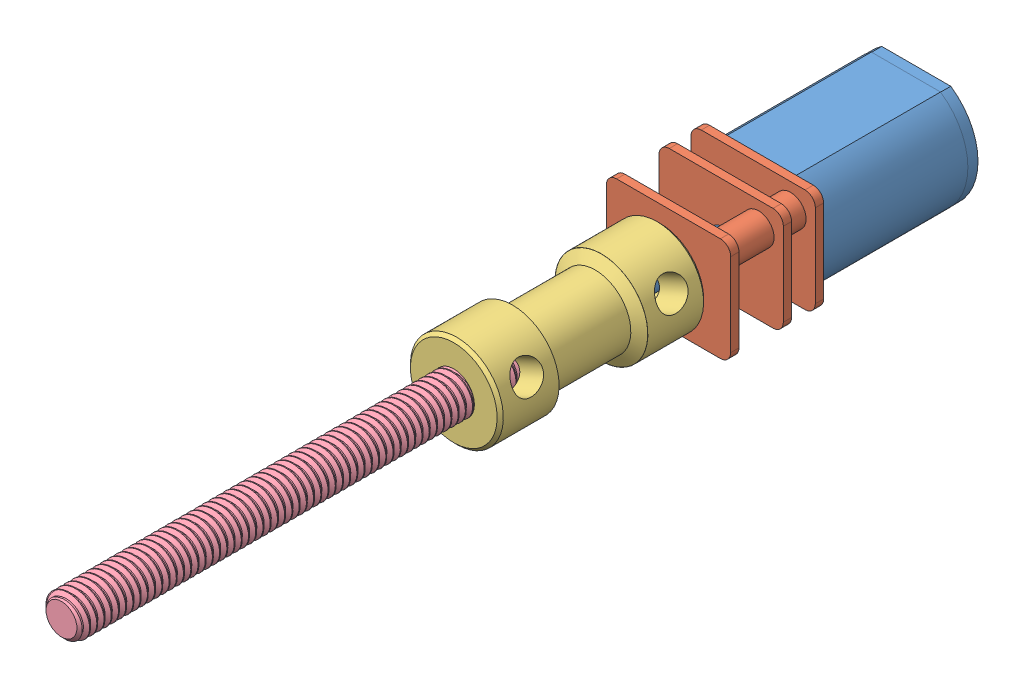
SolidWorks assembly MotorGearBox, configuration Default. Lengths in mm.
Overall size (12.05 11.9 84.89).
4 component instances, 4 part files, 8 mates.
Components (placement in the parent):
- Motor-1: Motor [Default] at origin size (12 10 32.2)
- GearBox-1: GearBox [Default] at (0 0 14) size (12.05 10.05 9.8)
- Coupling-1: Coupling [Default] at (0 0 23.8) x (-0.410622 0.911806 0) z (0 0 1) size (9 9 20)
- ThreadRod-1: ThreadRod [Default] at (0 0 33.8) x (-0.410622 0.911806 0) z (0 0 1) size (4.06 4.64 71.05)
Mates (geometry in assembly coordinates):
- Rovnoběžná1: parallel aligned: plane of Motor-1 through (-3.35 5 14) normal (0 1 0); plane of GearBox-1 through (-6.025 5.025 14.8) normal (0 1 0)
- Soustředná1: concentric aligned: cylinder of Motor-1 through (0 0 29.5) axis (0 0 -1) radius 1; cylinder of GearBox-1 through (0 0 23.8) axis (0 0 -1) radius 1.015
- Sjednocená5: coincident anti-aligned: plane of Motor-1 through (0.042 0 14) normal (0 0 1); plane of GearBox-1 through (0 0 14) normal (0 0 -1)
- Soustředná2: concentric aligned: cylinder of Motor-1 through (0 0 29.5) axis (0 0 -1) radius 1; cylinder of Coupling-1 through (0 0 43.8) axis (0 0 -1) radius 1.5
- Sjednocená6: coincident anti-aligned: plane of GearBox-1 through (0 0 23.8) normal (0 0 1); plane of Coupling-1 through (0 0 23.8) normal (0 0 -1)
- Sjednocená7: coincident anti-aligned: plane of Coupling-1 through (0 0 33.8) normal (0 0 1); plane of ThreadRod-1 through (0 0 33.8) normal (0 0 -1)
- Soustředná3: concentric aligned: cylinder of Coupling-1 through (0 0 33.8) axis (0 0 1) radius 2; circle of ThreadRod-1
- Sjednocená8: coincident aligned: plane of Coupling-1 through (0 0 23.8) normal (-0.911806 -0.410622 0); plane of ThreadRod-1 through (0 0 33.8) normal (-0.911806 -0.410622 0)
